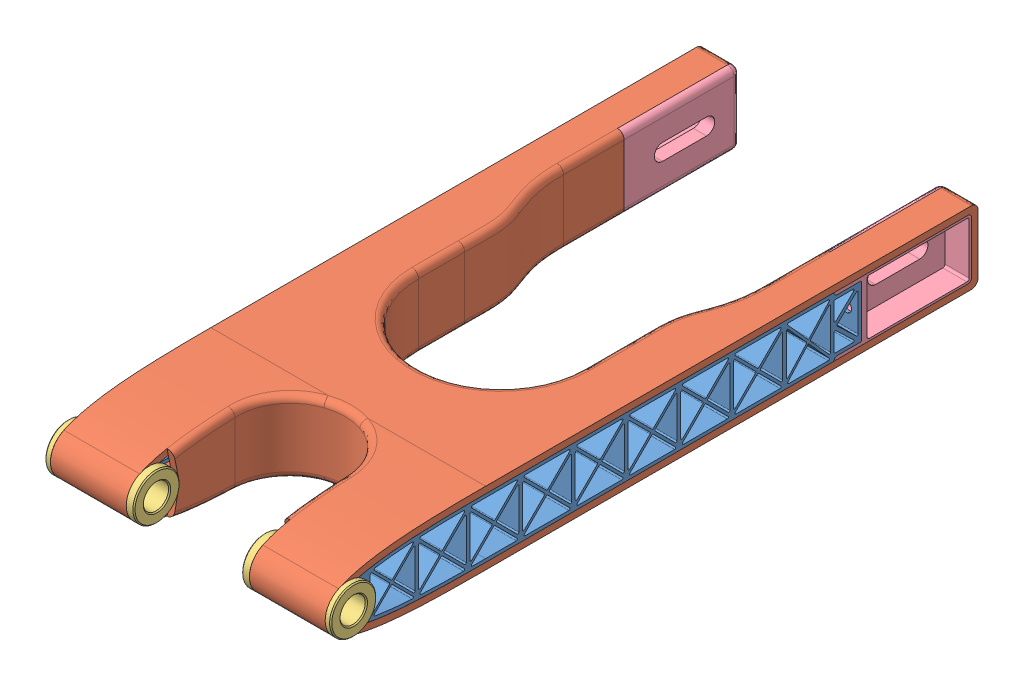
SolidWorks assembly Assembly, configuration Domyślna. Lengths in mm.
Overall size (260 131.73 594).
5 component instances, 5 part files, 5 mates.
Components (placement in the parent):
- ver_5.4_core-1: ver_5.4_core [Domyślna] at origin size (250 54 465.78)
- ver_5.4_thickness_6mm - Copy-2: ver_5.4_thickness_6mm - Copy [Domyślna] at origin size (256.52 76.11 594)
- ver_5.4_inserts_frame-2: ver_5.4_inserts_frame [Domyślna] at origin size (260 42 42)
- ver_5.4_inserts_wheel-2: ver_5.4_inserts_wheel [Domyślna] at origin size (250 66 156)
- ver_5.4_linkage-1: ver_5.4_linkage [Domyślna] at origin size (250 127.49 588)
Mates (geometry in assembly coordinates):
- Wspólnie1: coordinate: point of ver_5.4_core-1
- Wspólnie2: coordinate: unknown of ver_5.4_thickness_6mm - Copy-2
- Wspólnie3: coordinate: unknown of ver_5.4_inserts_frame-2
- Wspólnie4: coordinate: unknown of ver_5.4_inserts_wheel-2
- Wspólnie5: coordinate: unknown of ver_5.4_linkage-1
